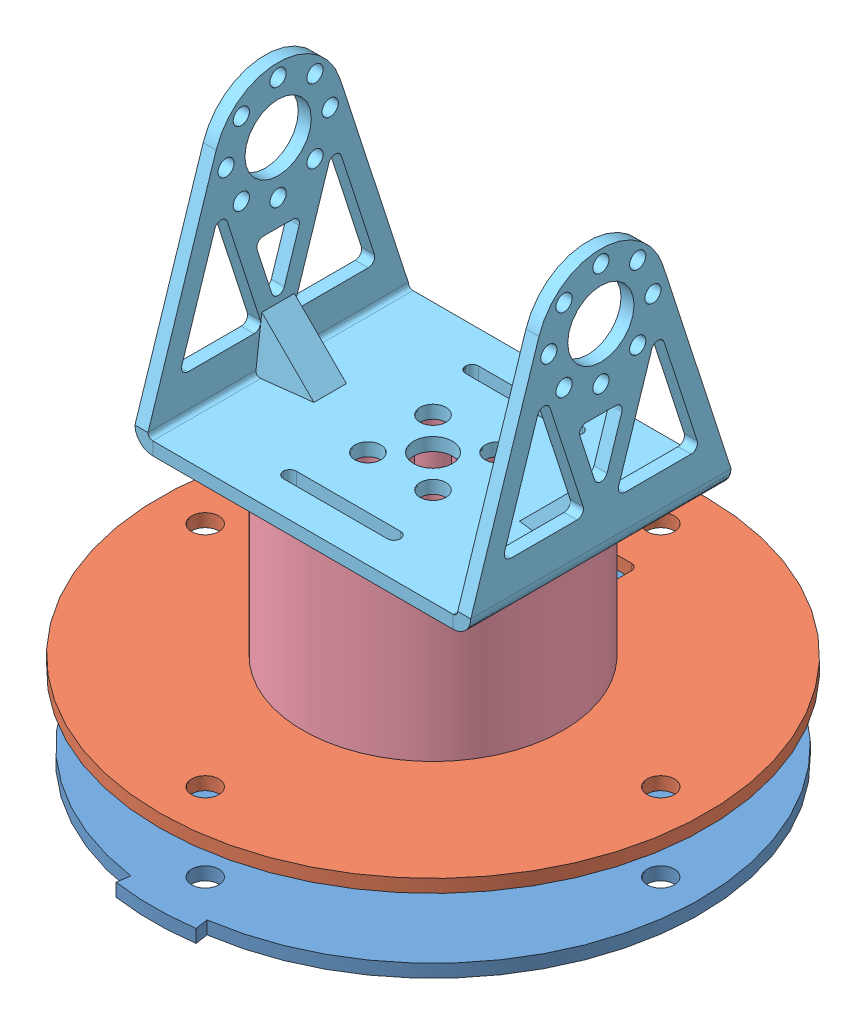
SolidWorks assembly shoulder, configuration 默认. Lengths in mm.
Overall size (84 84 85).
5 component instances, 5 part files, 15 mates.
Components (placement in the parent):
- 轴承底座-1: 轴承底座 [默认] at (0 5 0) size (82 2 84)
- 轴承顶-1: 轴承顶 [默认] at (0 17 0) size (84 2 84)
- 主舵盘-1: 主舵盘 [默认] at origin size (20 5 20)
- 12号舵机连接管-1: 12号舵机连接管 [默认] at (0 17 0) x (0 0 1) z (-1 0 0) size (40 25 40)
- 大U支架-1: 大U支架 [默认] at (0 44 0) size (51.6 42 40)
Mates (geometry in assembly coordinates):
- 距离1: distance = 10 mm anti-aligned: plane of 轴承顶-1 through (0 15 0) normal (0 -1 0); plane of 轴承底座-1 through (0 5 0) normal (0 1 0)
- 同心1: concentric aligned: circle of 轴承底座-1; circle of 轴承顶-1
- 同心2: concentric aligned: circle of 轴承底座-1; circle of 轴承顶-1
- 重合3: coincident anti-aligned: plane of 轴承底座-1 through (0 3 0) normal (0 -1 0); plane of 主舵盘-1 through (0 3 0) normal (0 1 0)
- 同心3: concentric aligned: circle of 轴承底座-1; circle of 主舵盘-1
- 同心4: concentric aligned: circle of 轴承底座-1; circle of 主舵盘-1
- 同心5: concentric aligned: circle of 轴承顶-1; circle of 12号舵机连接管-1
- 同心6: concentric aligned: circle of 轴承顶-1; circle of 12号舵机连接管-1
- 重合8: coincident anti-aligned: plane of 轴承顶-1 through (0 17 0) normal (0 1 0); plane of 12号舵机连接管-1 through (0 17 0) normal (0 -1 0)
- 重合9: coincident anti-aligned: plane of 12号舵机连接管-1 through (0 42 0) normal (0 1 0); plane of 大U支架-1 through (0 42 0) normal (0 -1 0)
- 同心7: concentric anti-aligned: circle of 12号舵机连接管-1; circle of 大U支架-1
- 同心8: concentric anti-aligned: circle of 12号舵机连接管-1; circle of 大U支架-1
- 重合12: coincident: plane of 主舵盘-1 through (0 0 0) normal (0 -1 0)
- 距离4: distance = 23.8 mm: plane of assembly; point of assembly; plane of 大U支架-1 through (23.8 44 0) normal (-1 0 0)
- 距离6: distance = 15 mm: plane of assembly; point of assembly; plane of 大U支架-1 through (-9 84.001 -15) normal (0 0 1)
